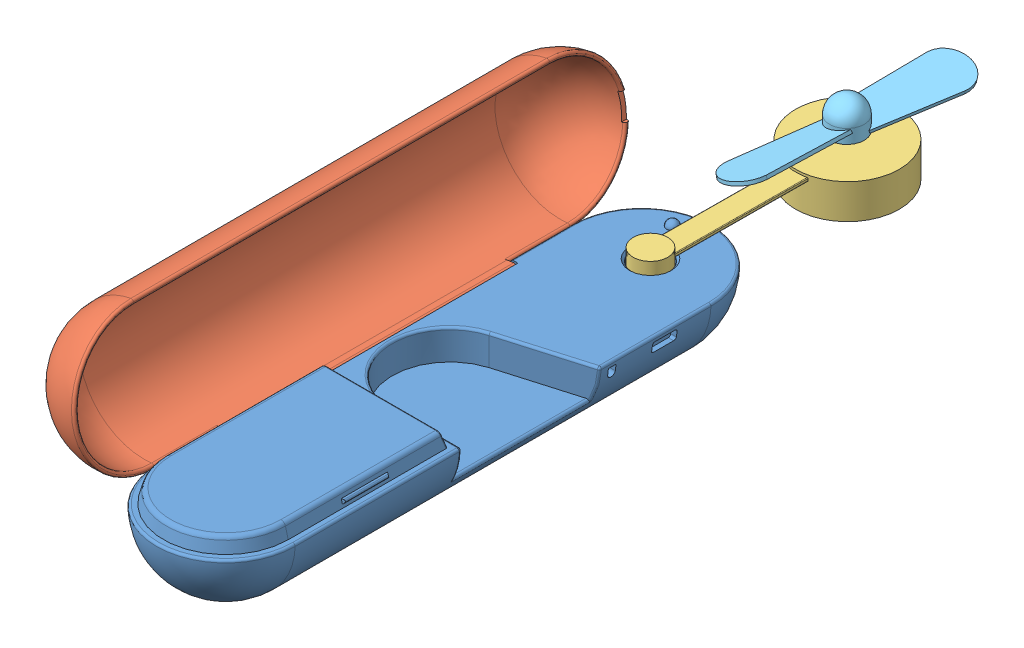
SolidWorks assembly 装配体1, configuration 默认. Lengths in mm.
Overall size (100.1 86.84 348.62).
5 component instances, 5 part files, 8 mates.
Components (placement in the parent):
- 底座-1: 底座 [默认] at origin size (59.97 36 239.97)
- 盖子-1: 盖子 [默认] at (-35.8831 26.6016 -0.3861) x (0 0 -1) z (0.152885 -0.988244 0) size (239.95 34 59.98)
- 转动轴-1: 转动轴 [默认] at (0.5834 -4.8297 -178.4975) x (-0.006888 0 0.999976) z (-0.999976 0 -0.006888) size (114.7 16.55 45)
- 六棱柱-1: 六棱柱 [默认] at (0.5834 9.1703 -178.4975) x (0.512933 0 -0.858428) z (0 -1 0) size (2 2 10)
- 扇叶-1: 扇叶 [默认] at (0.5834 12.1703 -178.4975) x (-0.099023 0 0.995085) z (0.995085 0 0.099023) size (99.4 13.5 20.09)
Mates (geometry in assembly coordinates):
- 宽度4: width anti-aligned: plane of 底座-1 through (-27 21 61.6239) normal (0 0 -1); plane of 底座-1 through (-27 21 -63.3761) normal (0 0 1); plane of 盖子-1 through (-27.6494 -0.4577 61.5239) normal (0 0 1); plane of 盖子-1 through (-27.6494 -0.4577 -63.2761) normal (0 0 -1)
- 同心4: concentric aligned: circle of 底座-1; circle of 转动轴-1
- 距离2: distance = 0.2 mm anti-aligned: plane of 转动轴-1 through (5.7383 0.2 -200.9645) normal (0 -1 0); plane of 底座-1 through (0 0 90) normal (0 1 0)
- 重合6: coincident anti-aligned: plane of 转动轴-1 through (0.5834 -0.8297 -178.4975) normal (0 1 0); plane of 六棱柱-1 through (0.5834 -0.8297 -178.4975) normal (0 -1 0)
- 同心5: concentric anti-aligned: circle of 转动轴-1; circle of 六棱柱-1
- 距离4: distance = 4 mm anti-aligned: plane of 六棱柱-1 through (0.5834 9.1703 -178.4975) normal (0 1 0); plane of 扇叶-1 through (0.5834 13.1703 -178.4975) normal (0 -1 0)
- 同心22: concentric anti-aligned: cylinder of 六棱柱-1 through (0.5834 -0.8297 -178.4975) axis (0 1 0) radius 1; cylinder of 扇叶-1 through (0.5834 13.1703 -178.4975) axis (0 -1 0) radius 1
- 同心23: concentric: cylinder of 底座-1 through (-28.5 -1.5 -70.9318) axis (0 0 1) radius 0.55; sphere of 盖子-1
